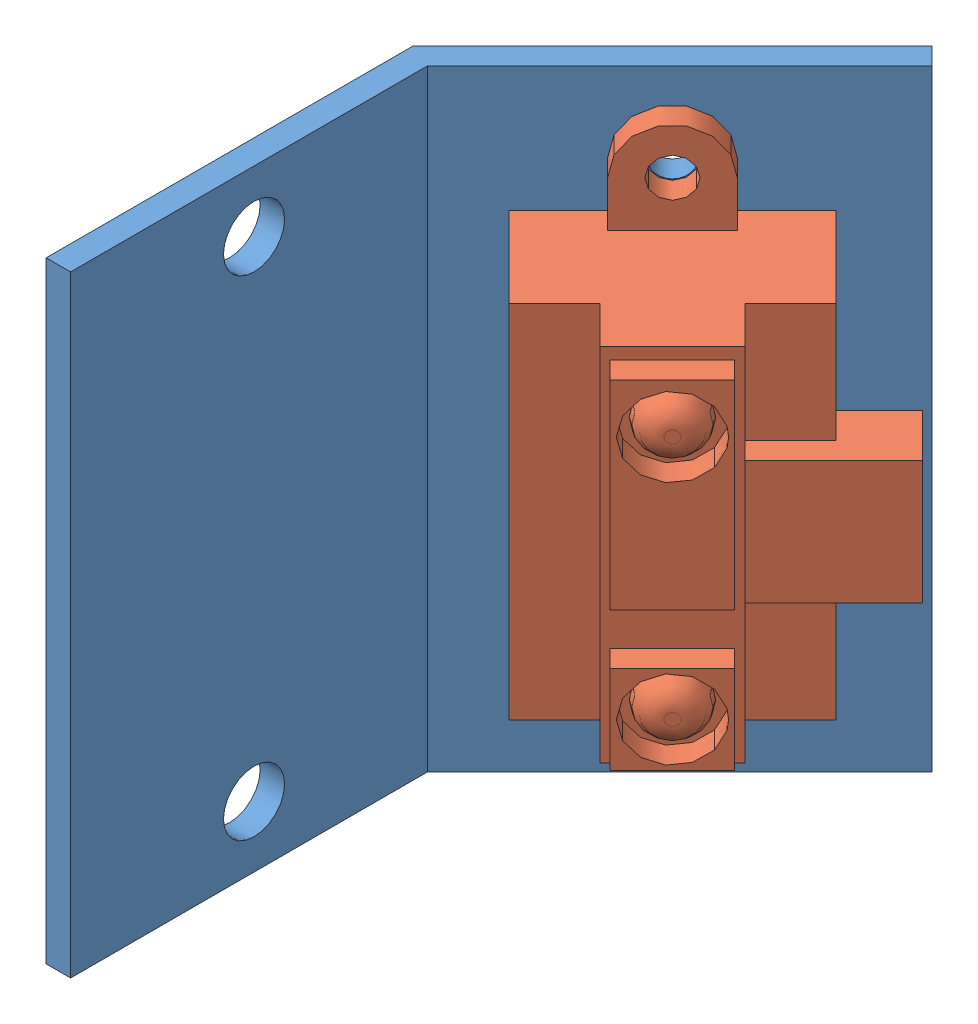
SolidWorks assembly test_porte_capteur_1, configuration Défaut. Lengths in mm.
Overall size (33.27 50 51.21).
2 component instances, 2 part files, 3 mates.
Components (placement in the parent):
- Attache_A45_L60_h50-1: Attache_A45_L60_h50 [Défaut] at (-17.7797 -5.8574 0) size (22.63 50 51.21)
- GP2D12-1: GP2D12 [Default] at (0.9233 4.3926 -45.8745) x (0 1 0) z (0.707107 0 -0.707107) size (44.5 15.6 23.9)
Mates (geometry in assembly coordinates):
- Coïncidente1: coincident: plane of ? through (-10.4445 3.7169 -34.5067) normal (-0.707107 0 -0.707107); plane of Attache_A45_L60_h50-1 through (4.8477 44.1426 -49.799) normal (0.707107 0 0.707107)
- Coaxiale1: concentric: cylinder of Attache_A45_L60_h50-1; cylinder of ?
- Coaxiale2: concentric aligned: cylinder of Attache_A45_L60_h50-1; cylinder of ?
